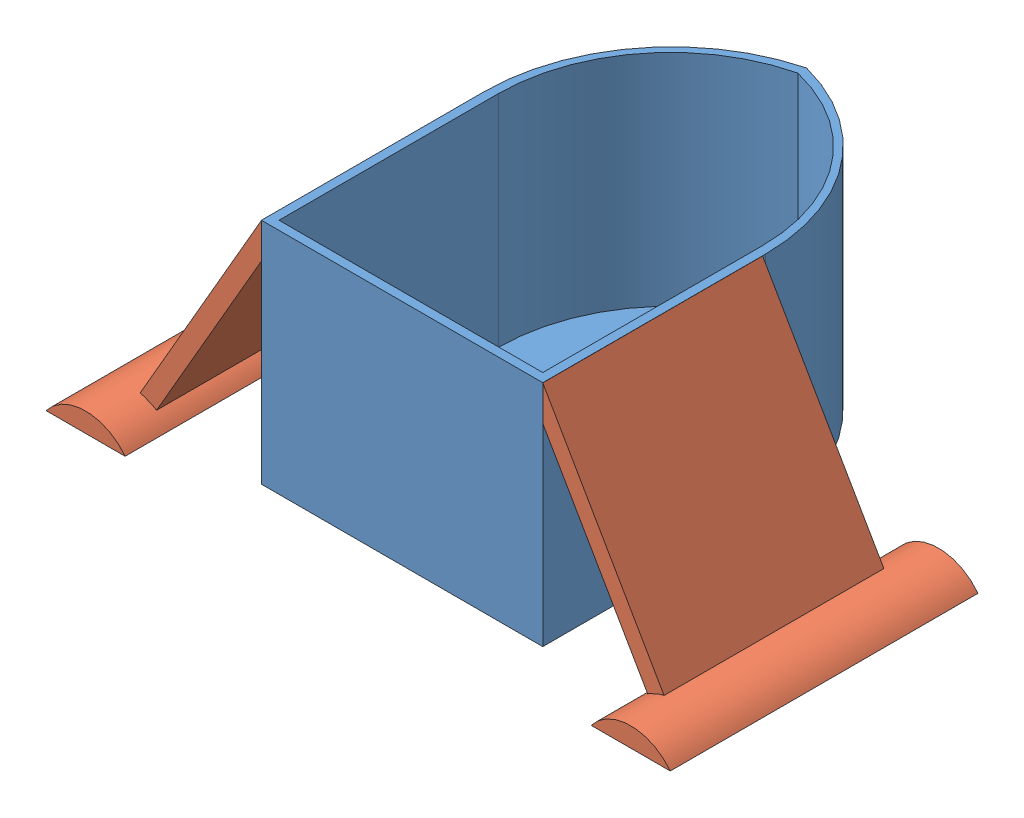
SolidWorks assembly Boat Hull Assembly, configuration Default. Lengths in mm.
Overall size (180.34 66.04 129.54).
3 component instances, 2 part files, 3 mates.
Components (placement in the parent):
- Boat Body-2: Boat Body [Default] at origin size (81.28 66.04 116.84)
- Boat Arm-3: Boat Arm [Default] at (0 0 12.7) size (49.53 65.99 88.9)
- Boat Arm-4: Boat Arm [Default] at (0 0 -76.2) x (-1 0 0) z (0 0 -1) size (49.53 65.99 88.9)
Mates (geometry in assembly coordinates):
- Coincident8: coincident anti-aligned: plane of Boat Body-2 through (40.64 66.04 0) normal (1 0 0); plane of Boat Arm-3 through (40.64 65.9911 -63.5) normal (-1 0 0)
- Coincident9: coincident aligned: plane of Boat Body-2 through (-13.6064 0 -64.3278) normal (0 -1 0); plane of Boat Arm-3 through (90.17 0 -76.2) normal (0 -1 0)
- Coincident10: coincident aligned: plane of Boat Body-2 through (40.64 66.04 0) normal (0 0 1); plane of Boat Arm-3 through (80.796 -13.721 0) normal (0 0 1)
